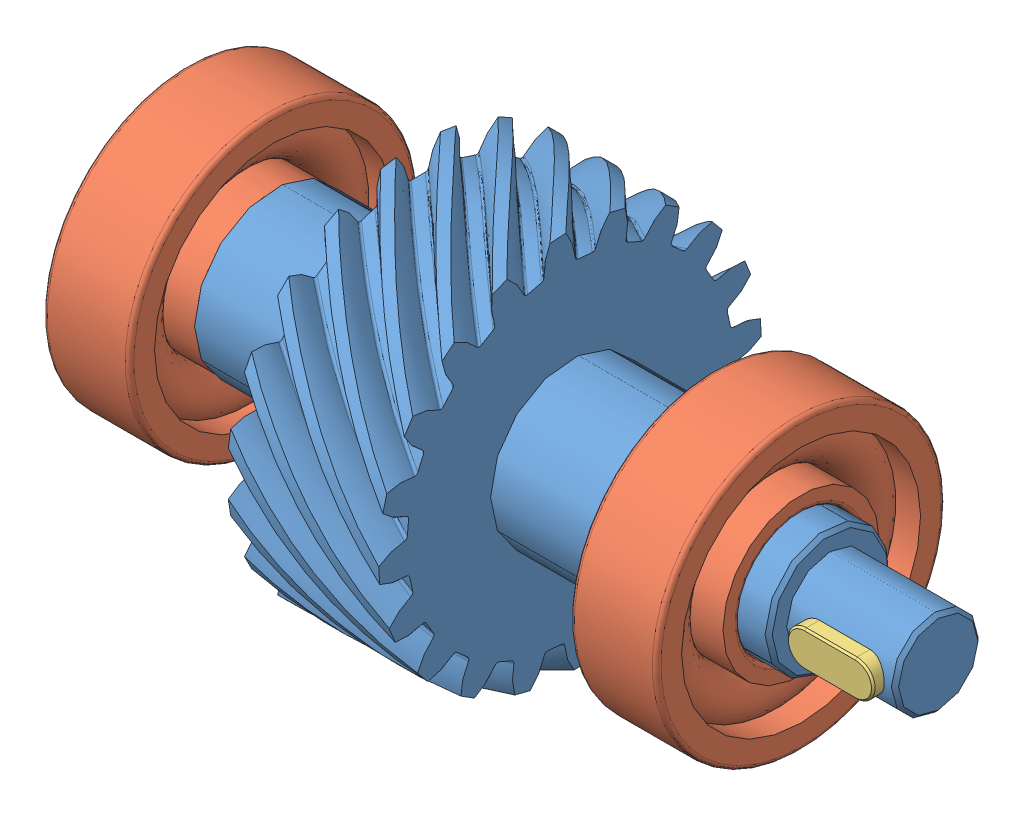
SolidWorks assembly Assem4, configuration Default. Lengths in mm.
Overall size (104 53.9 53.9).
5 component instances, 4 part files, 11 mates.
Components (placement in the parent):
- ISO - RH Helical gear 1.75M 20T 45HA 20PA 21FW ---20A75H50L0.8N-1: ISO - RH Helical gear 1.75M 20T 45HA 20PA 21FW ---20A75H50L0.8N [ISO - RH Helical gear 1.75M 20T 45HA 20PA 21FW ---20A75H50L0.8N] at (-20.123 -3.3202 2.3206) size (104 53.9 53.9)
- ISO 15 ABB - 0217 - 10,SI,NC,10_68-1: ISO 15 ABB - 0217 - 10,SI,NC,10_68 [ISO 15 ABB - 0217 - 10,SI,NC,10_68] at (26.877 -3.3202 2.3206) size (12 40 40)
- ISO 15 ABB - 0217 - 10,SI,NC,10_68-2: ISO 15 ABB - 0217 - 10,SI,NC,10_68 [ISO 15 ABB - 0217 - 10,SI,NC,10_68] at (-46.123 -3.3202 2.3206) size (12 40 40)
- Part4-1: Part4 [Default] at (58.877 -3.3202 2.3206) x (0 -1 0) z (-1 0 0) (suppressed, hidden)
- Key ISO 2491 5x3-12-A-1: Key ISO 2491 5x3-12-A [Key ISO 2491 5x3-12-A] at (47.877 -3.3202 6.8206) size (12 5 3)
Mates (geometry in assembly coordinates):
- Concentric1: concentric anti-aligned: cylinder of ISO - RH Helical gear 1.75M 20T 45HA 20PA 21FW ---20A75H50L0.8N-1 through (36.877 -3.3202 2.3206) axis (-1 0 0) radius 8.5; cylinder of ISO 15 ABB - 0217 - 10,SI,NC,10_68-1 through (6.2395 -3.3202 2.3206) axis (1 0 0) radius 8.5
- Concentric2: concentric aligned: cylinder of ISO - RH Helical gear 1.75M 20T 45HA 20PA 21FW ---20A75H50L0.8N-1 through (51.877 -3.3202 2.3206) axis (-1 0 0) radius 6; cylinder of Part4-1 through (139.9639 -3.3202 2.3206) axis (-1 0 0) radius 6
- Concentric3: concentric aligned: cylinder of ISO - RH Helical gear 1.75M 20T 45HA 20PA 21FW ---20A75H50L0.8N-1 through (-52.123 -3.3202 2.3206) axis (1 0 0) radius 8.5; cylinder of ISO 15 ABB - 0217 - 10,SI,NC,10_68-2 through (-66.7605 -3.3202 2.3206) axis (1 0 0) radius 8.5
- Coincident1: coincident aligned: plane of ISO - RH Helical gear 1.75M 20T 45HA 20PA 21FW ---20A75H50L0.8N-1 through (-52.123 -3.3202 2.3206) normal (-1 0 0); plane of ISO 15 ABB - 0217 - 10,SI,NC,10_68-2 through (-52.123 8.6298 2.3206) normal (-1 0 0)
- Coincident2: coincident anti-aligned: plane of ISO - RH Helical gear 1.75M 20T 45HA 20PA 21FW ---20A75H50L0.8N-1 through (20.877 -3.3202 2.3206) normal (1 0 0); plane of ISO 15 ABB - 0217 - 10,SI,NC,10_68-1 through (20.877 8.6298 2.3206) normal (-1 0 0)
- Coincident3: coincident anti-aligned: plane of Part4-1 through (139.9639 -5.8202 9.8206) normal (0 1 0); plane of Key ISO 2491 5x3-12-A-1 through (40.877 -5.8202 9.8206) normal (0 -1 0)
- Coincident4: coincident anti-aligned: plane of Part4-1 through (139.9639 -0.8202 9.8206) normal (0 0 -1); plane of Key ISO 2491 5x3-12-A-1 through (47.877 -3.3202 9.8206) normal (0 0 1)
- Coincident5: coincident anti-aligned: plane of ISO - RH Helical gear 1.75M 20T 45HA 20PA 21FW ---20A75H50L0.8N-1 through (47.877 -5.8202 6.8206) normal (0 1 0); plane of Key ISO 2491 5x3-12-A-1 through (40.877 -5.8202 9.8206) normal (0 -1 0)
- Coincident6: coincident anti-aligned: plane of ISO - RH Helical gear 1.75M 20T 45HA 20PA 21FW ---20A75H50L0.8N-1 through (47.877 -3.3202 6.8206) normal (0 0 1); plane of Key ISO 2491 5x3-12-A-1 through (47.877 -3.3202 6.8206) normal (0 0 -1)
- Concentric4: concentric anti-aligned: cylinder of ISO - RH Helical gear 1.75M 20T 45HA 20PA 21FW ---20A75H50L0.8N-1 through (40.877 -3.3202 6.8206) axis (0 0 1) radius 2.5; cylinder of Key ISO 2491 5x3-12-A-1 through (40.877 -3.3202 9.8206) axis (0 0 -1) radius 2.5
- Coincident7: coincident anti-aligned: plane of ISO - RH Helical gear 1.75M 20T 45HA 20PA 21FW ---20A75H50L0.8N-1 through (36.877 -3.3202 2.3206) normal (1 0 0); plane of Part4-1 through (36.877 -3.3202 2.3206) normal (-1 0 0)
